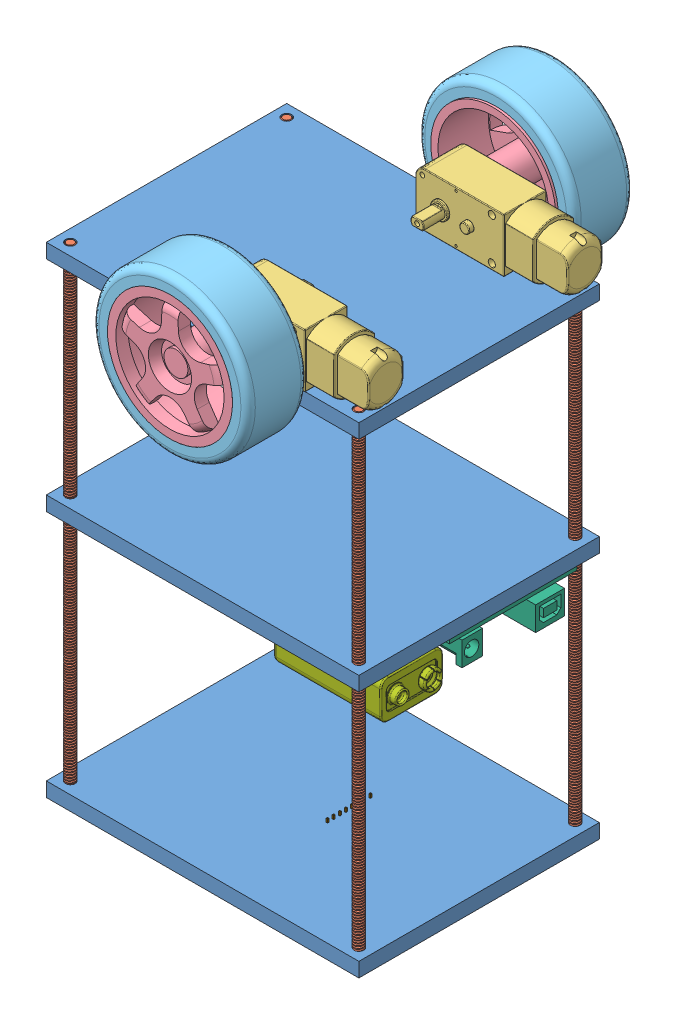
SolidWorks assembly Digital Project, configuration Default. Lengths in mm.
Overall size (133.87 247.26 161.08).
39 component instances, 15 part files, 33 mates.
Components (placement in the parent):
- Part1-1: Part1 [Default] at (69.1496 26.2648 115.1112) size (130 6 100)
- Part2-1: Part2 [Default] at (9.1496 226.2648 160.1112) x (-0.873969 0 -0.485982) z (0 -1 0) size (4.1 4.62 200.58)
- Part2-3: Part2 [Default] at (129.1496 226.2648 160.1112) x (1 0 0) z (0 -1 0) size (4.1 4.62 200.58)
- Part2-4: Part2 [Default] at (9.1496 226.2648 70.1112) x (1 0 0) z (0 -1 0) size (4.1 4.62 200.58)
- Part2-5: Part2 [Default] at (129.1496 226.2648 70.1112) x (1 0 0) z (0 -1 0) size (4.1 4.62 200.58)
- Part1-2: Part1 [Default] at (69.1496 220.2648 115.1112) x (1 0 0) z (0 0 1) size (130 6 100)
- Part1-3: Part1 [Default] at (69.1496 129.2648 115.1112) x (1 0 0) z (0 0 1) size (130 6 100)
- DC Motor_Yellow Gear box-1: DC Motor_Yellow Gear box [Default] at (75.1752 237.4648 156.5612) x (0 -1 0) z (0 0 1) size (22.4 66.75 37.7)
- DC Motor_Yellow Gear box-2: DC Motor_Yellow Gear box [Default] at (75.042 237.4648 73.6612) x (0 -1 0) z (0 0 1) size (22.4 66.75 37.7)
- rim-1: rim [Default] at (85.8752 237.4648 195.4112) x (1 0 0) z (0 1 0) size (52 30.24 52)
- rim-2: rim [Default] at (85.742 237.4648 34.8112) x (1 0 0) z (0 -1 0) size (52 30.24 52)
- tire-1: tire [Default] at (85.742 237.4648 47.3112) x (1 0 0) z (0 0 1) size (65 65 25)
- tire-2: tire [Default] at (85.8752 237.4648 182.9112) x (1 0 0) z (0 0 1) size (65 65 25)
- Audrino-1: Audrino [Default] at (31.1496 129.2648 122.4597) x (0 0 -1) z (-1 0 0) size (53 11.5 106.87)
- Battery 9V-1: Battery 9V [Default] at (96.9263 107.2607 144.7927) x (0 0 1) z (0 1 0) size (25.91 48.13 16.26)
- MPU 6050 IMU-1: MPU 6050 IMU [Default] at (87.3753 36.6517 119.7574) x (0 0 -1) z (-1 0 0) size (21.11 11.18 15.88)
  - Base-1: Base [Default] at (7.2489 10.9584 16.5726) size (21.11 1.14 15.75)
  - pin header-1: pin header [Default] at (16.0246 10.3869 9.8416) x (-1 0 0) z (0 0 1) size (2.54 11.18 2.54)
  - pin header-2: pin header [Default] at (13.4846 10.3869 9.8416) x (-1 0 0) z (0 0 1) size (2.54 11.18 2.54)
  - pin header-3: pin header [Default] at (10.9446 10.3869 9.8416) x (-1 0 0) z (0 0 1) size (2.54 11.18 2.54)
  - pin header-4: pin header [Default] at (8.4046 10.3869 9.8416) x (-1 0 0) z (0 0 1) size (2.54 11.18 2.54)
  - pin header-5: pin header [Default] at (5.8646 10.3869 9.8416) x (-1 0 0) z (0 0 1) size (2.54 11.18 2.54)
  - pin header-6: pin header [Default] at (3.3246 10.3869 9.8416) x (-1 0 0) z (0 0 1) size (2.54 11.18 2.54)
  - pin header-7: pin header [Default] at (0.7846 10.3869 9.8416) x (-1 0 0) z (0 0 1) size (2.54 11.18 2.54)
  - pin header-8: pin header [Default] at (-1.7554 10.3869 9.8416) x (-1 0 0) z (0 0 1) size (2.54 11.18 2.54)
  - sensor chip-1: sensor chip [Default] at (7.2489 11.5499 17.4466) size (5.4 0.9 5.4)
  - S2NH chip-1: S2NH chip [Default] at (16.1026 12.3799 16.5726) size (3 1.35 3.65)
  - Resistor small-3: Resistor small [Default] at (16.1026 11.5314 19.3726) size (2.75 0.99 1)
  - Resistor small-4: Resistor small [Default] at (13.9776 11.5314 15.6976) x (0 0 -1) z (1 0 0) size (2.75 0.99 1)
  - Resistor small black-3: Resistor small black [Default] at (12.6276 11.5299 15.6976) x (0 0 1) z (-1 0 0) size (2.45 0.6 1.02)
  - Resistor small black-4: Resistor small black [Default] at (11.1276 11.5299 15.6976) x (0 0 1) z (-1 0 0) size (2.45 0.6 1.02)
  - Resistor small-5: Resistor small [Default] at (12.6276 11.5314 19.3216) x (0 0 -1) z (1 0 0) size (2.75 0.99 1)
  - Resistor small-6: Resistor small [Default] at (11.1276 11.5314 19.3216) x (0 0 -1) z (1 0 0) size (2.75 0.99 1)
  - Resistor small-7: Resistor small [Default] at (3.3702 11.5314 19.3216) x (0 0 -1) z (1 0 0) size (2.75 0.99 1)
  - Resistor small black-5: Resistor small black [Default] at (1.8702 11.5299 15.6972) x (0 0 -1) z (1 0 0) size (2.45 0.6 1.02)
  - Resistor small-8: Resistor small [Default] at (3.3702 11.5314 15.6976) x (0 0 1) z (-1 0 0) size (2.75 0.99 1)
  - Small LED-1: Small LED [Default] at (0.3652 11.5299 15.6976) size (0.85 0.84 1.9)
  - Resistor small black-6: Resistor small black [Default] at (1.8702 11.5299 19.3216) x (0 0 1) z (-1 0 0) size (2.45 0.6 1.02)
  - Resistor black-1: Resistor black [Default] at (7.2489 12.3799 21.6466) size (4.2 1.6 1.6)
Mates (geometry in assembly coordinates):
- Coincident3: coincident aligned: plane of Part1-1 through (69.1496 26.2648 115.1112) normal (0 -1 0); plane of Part2-1 through (9.1496 26.2648 160.1112) normal (0 -1 0)
- Tangent3: tangent: cylinder of Part1-1 through (9.1496 26.2648 160.1112) axis (0 1 0) radius 2; curve of Part2-1
- Coincident4: coincident aligned: plane of Part1-1 through (69.1496 26.2648 115.1112) normal (0 -1 0); plane of Part2-3 through (129.1496 26.2648 160.1112) normal (0 -1 0)
- Tangent8: tangent: cylinder of Part1-1 through (129.1496 26.2648 160.1112) axis (0 1 0) radius 2; curve of Part2-3
- Coincident5: coincident aligned: plane of Part1-1 through (69.1496 26.2648 115.1112) normal (0 -1 0); plane of Part2-4 through (9.1496 26.2648 70.1112) normal (0 -1 0)
- Concentric1: concentric aligned: cylinder of Part1-1 through (9.1496 26.2648 70.1112) axis (0 1 0) radius 2; cylinder of Part2-4 through (9.1496 26.2648 70.1112) axis (0 1 0) radius 2
- Coincident6: coincident aligned: plane of Part1-1 through (69.1496 26.2648 115.1112) normal (0 -1 0); plane of Part2-5 through (129.1496 26.2648 70.1112) normal (0 -1 0)
- Concentric2: concentric aligned: cylinder of Part1-1 through (129.1496 26.2648 70.1112) axis (0 1 0) radius 2; cylinder of Part2-5 through (129.1496 26.2648 70.1112) axis (0 1 0) radius 2
- Coincident7: coincident aligned: plane of Part2-1 through (9.1496 226.2648 160.1112) normal (0 1 0); plane of Part1-2 through (69.1496 226.2648 115.1112) normal (0 1 0)
- Concentric3: concentric aligned: cylinder of Part2-1 through (9.1496 26.2648 160.1112) axis (0 1 0) radius 2; cylinder of Part1-2 through (9.1496 220.2648 160.1112) axis (0 1 0) radius 2
- Concentric4: concentric aligned: cylinder of Part2-5 through (129.1496 26.2648 70.1112) axis (0 1 0) radius 2; cylinder of Part1-2 through (129.1496 220.2648 70.1112) axis (0 1 0) radius 2
- Concentric6: concentric aligned: cylinder of Part2-1 through (9.1496 26.2648 160.1112) axis (0 1 0) radius 2; cylinder of Part1-3 through (9.1496 129.2648 160.1112) axis (0 1 0) radius 2
- Concentric7: concentric aligned: cylinder of Part2-4 through (9.1496 26.2648 70.1112) axis (0 1 0) radius 2; cylinder of Part1-3 through (9.1496 129.2648 70.1112) axis (0 1 0) radius 2
- Distance2: distance = 97 mm anti-aligned: plane of Part1-1 through (69.1496 32.2648 115.1112) normal (0 1 0); plane of Part1-3 through (69.1496 129.2648 115.1112) normal (0 -1 0)
- Lock4: lock: unknown of Part1-2; unknown of DC Motor_Yellow Gear box-1
- Coincident14: coincident anti-aligned: plane of Part1-2 through (69.1496 226.2648 115.1112) normal (0 1 0); plane of DC Motor_Yellow Gear box-1 through (111.9752 226.2648 147.7112) normal (0 -1 0)
- Lock3: lock: unknown of Part1-2; unknown of DC Motor_Yellow Gear box-2
- Coincident17: coincident anti-aligned: line of Part1-2 through (134.1496 226.2648 65.1112) axis (-1 0 0); line of DC Motor_Yellow Gear box-2 through (79.042 226.2648 65.1112) axis (1 0 0)
- Coincident29: coincident anti-aligned: plane of DC Motor_Yellow Gear box-1 through (111.9752 248.6648 165.4112) normal (0 0 1); plane of rim-1 through (85.8752 237.4648 165.4112) normal (0 0 -1)
- Concentric9: concentric aligned: cylinder of DC Motor_Yellow Gear box-1 through (85.8752 237.4648 175.4112) axis (0 0 -1) radius 2.7; cylinder of rim-1 through (85.8752 237.4648 173.4112) axis (0 0 -1) radius 2.7
- Coincident30: coincident anti-aligned: plane of DC Motor_Yellow Gear box-2 through (111.842 248.6648 64.8112) normal (0 0 -1); plane of rim-2 through (85.742 237.4648 64.8112) normal (0 0 1)
- Concentric10: concentric aligned: cylinder of DC Motor_Yellow Gear box-2 through (85.742 237.4648 54.8112) axis (0 0 1) radius 2.7; cylinder of rim-2 through (85.742 237.4648 56.8112) axis (0 0 1) radius 2.7
- Concentric11: concentric aligned: cylinder of rim-2 through (85.742 237.4648 60.8112) axis (0 0 -1) radius 26; cylinder of tire-1 through (85.742 237.4648 59.8112) axis (0 0 -1) radius 26
- Coincident31: coincident aligned: plane of rim-2 through (85.742 237.4648 34.8112) normal (0 0 -1); plane of tire-1 through (85.742 237.4648 34.8112) normal (0 0 -1)
- Concentric12: concentric anti-aligned: cylinder of rim-1 through (85.8752 237.4648 169.4112) axis (0 0 1) radius 26; cylinder of tire-2 through (85.8752 237.4648 195.4112) axis (0 0 -1) radius 26
- Coincident32: coincident aligned: plane of rim-1 through (85.8752 237.4648 195.4112) normal (0 0 1); plane of tire-2 through (85.8752 237.4648 195.4112) normal (0 0 1)
- Lock1: lock: unknown of Part1-3; unknown of Audrino-1
- Coincident34: coincident anti-aligned: line of Part1-3 through (134.1496 129.2648 165.1112) axis (0 0 -1); line of Audrino-1 through (134.1496 129.2648 74.4597) axis (0 0 1)
- Coincident37: coincident anti-aligned: plane of Part1-3 through (69.1496 129.2648 115.1112) normal (0 -1 0); plane of Battery 9V-1 through (134.6576 129.2648 130.6272) normal (0 1 0)
- Coincident38: coincident aligned: line of Part1-3 through (134.1496 129.2648 165.1112) axis (0 0 -1); line of Battery 9V-1 through (134.1496 129.2648 153.3602) axis (0 0 -1)
- Lock2: lock: unknown of Audrino-1; unknown of Battery 9V-1
- Lock5: lock: unknown of Part1-1; unknown of MPU 6050 IMU-1/Base-1
- Parallel7: parallel: line of Part1-1 through (134.1496 26.2648 165.1112) axis (0 0 -1); line of MPU 6050 IMU-1/Base-1 through (62.9287 25.1218 123.0622) axis (0 0 -1)
